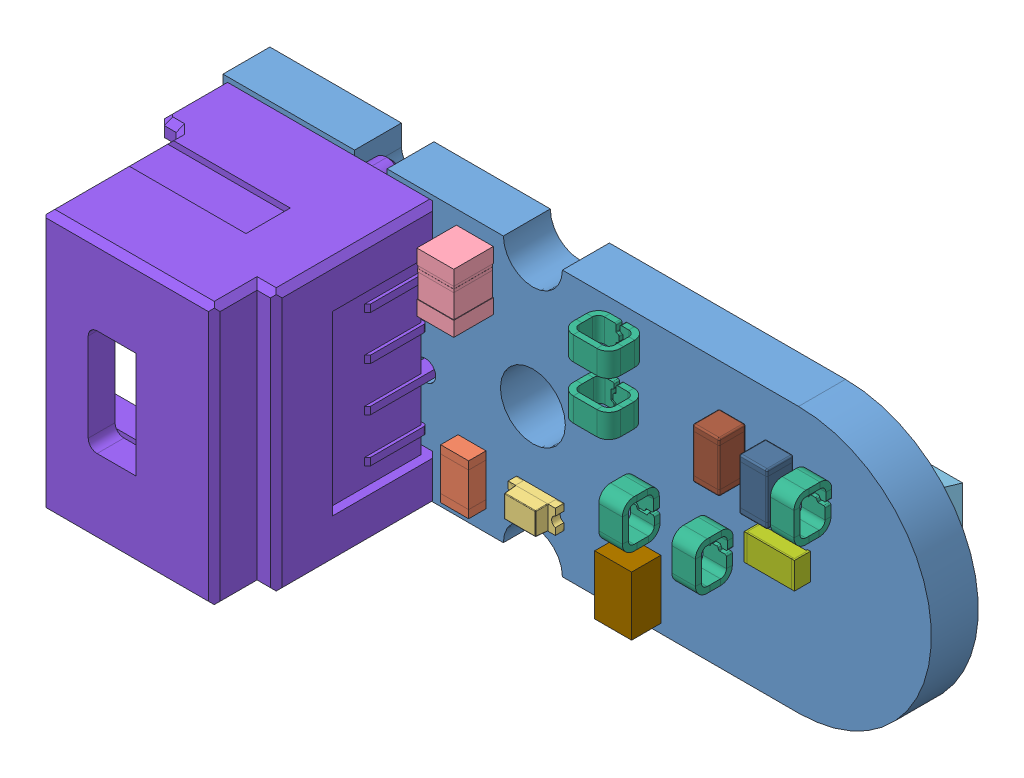
SolidWorks assembly Encoder_Board_-_End, configuration Default. Lengths in mm.
Overall size (24 9 10.35).
15 component instances, 11 part files, 0 mates.
Components (placement in the parent):
- Encoder_Board_-_End_BOARD-1: Encoder_Board_-_End_BOARD [Default] at origin size (24 9 1.59)
- RESC0603(1608)_N_CMP-009-00178-1-1: RESC0603(1608)_N_CMP-009-00178-1 [Default] at (31.4385 87.0536 1.58) x (0 -1 0) z (0 0 1) size (1.7 0.95 0.6)
- WL-SMCW_0603_150060xx75000_CMP-007-00036-1-1: WL-SMCW_0603_150060xx75000_CMP-007-00036-1 [Default] at (33.7499 87.2822 1.58) size (1.6 0.8 0.7)
- CAP_CER_10UF_16V_X5R_0805-Footprint-1_CMP-001-00084-6-1: CAP_CER_10UF_16V_X5R_0805-Footprint-1_CMP-001-00084-6 [Default] at (31.5344 93.0226 1.58) x (0 -1 0) z (0 0 1) size (2 1.25 1.35)
- AS5600L-ASOM-Footprint-1_CMP-010-00024-5-1: AS5600L-ASOM-Footprint-1_CMP-010-00024-5 [Default] at (42.5 90 0.01) x (0 -1 0) z (0 0 -1) size (6 4.91 1.76)
- FP-S2761-46R-MFG_CMP-002-00072-5-1: FP-S2761-46R-MFG_CMP-002-00072-5 [Default] at (37.4018 89.1396 1.58) x (0 -1 0) z (0 0 1) size (1.6 0.8 1.28)
- FP-S2761-46R-MFG_CMP-002-00072-5-2: FP-S2761-46R-MFG_CMP-002-00072-5 [Default] at (36.5382 93.6576 1.58) size (1.6 0.8 1.28)
- FP-S2761-46R-MFG_CMP-002-00072-5-3: FP-S2761-46R-MFG_CMP-002-00072-5 [Default] at (39.877 89.1396 1.58) x (0 1 0) z (0 0 1) size (1.6 0.8 1.28)
- FP-S2761-46R-MFG_CMP-002-00072-5-4: FP-S2761-46R-MFG_CMP-002-00072-5 [Default] at (36.5382 91.8622 1.58) x (-1 0 0) z (0 0 1) size (1.6 0.8 1.28)
- FP-S2761-46R-MFG_CMP-002-00072-5-5: FP-S2761-46R-MFG_CMP-002-00072-5 [Default] at (43.217 92.2352 1.58) x (0 1 0) z (0 0 1) size (1.6 0.8 1.28)
- RESC1608X55X25NL10T15_CMP-009-00017-7-1: RESC1608X55X25NL10T15_CMP-009-00017-7 [Default] at (42.05 90 1.58) x (-1 0 0) z (0 0 1) size (1.7 0.9 0.55)
- 5031750400-Footprint-1_CMP-002-00074-2-1: 5031750400-Footprint-1_CMP-002-00074-2 [Default] at (29.858 92.238 1.58) x (0 -1 0) z (0 0 1) size (8.9 7.25 10.35)
- ONSC-SC-70-3-419-04_V_CMP-004-00039-1-1: ONSC-SC-70-3-419-04_V_CMP-004-00039-1 [Default] at (37.2088 86.801 1.58) x (-1 0 0) z (0 0 1) size (1.25 2 1)
- CAPC1608X90X35NL15T15_CMP-001-00004-8-1: CAPC1608X90X35NL15T15_CMP-001-00004-8 [Default] at (41.8468 92.1086 1.58) x (0 1 0) z (0 0 1) size (1.75 0.95 0.9)
- CAPC1608X90X40NL10T20_CMP-001-00017-8-1: CAPC1608X90X40NL10T20_CMP-001-00017-8 [Default] at (40.2494 92.2352 1.58) x (0 1 0) z (0 0 1) size (1.7 0.9 0.9)
